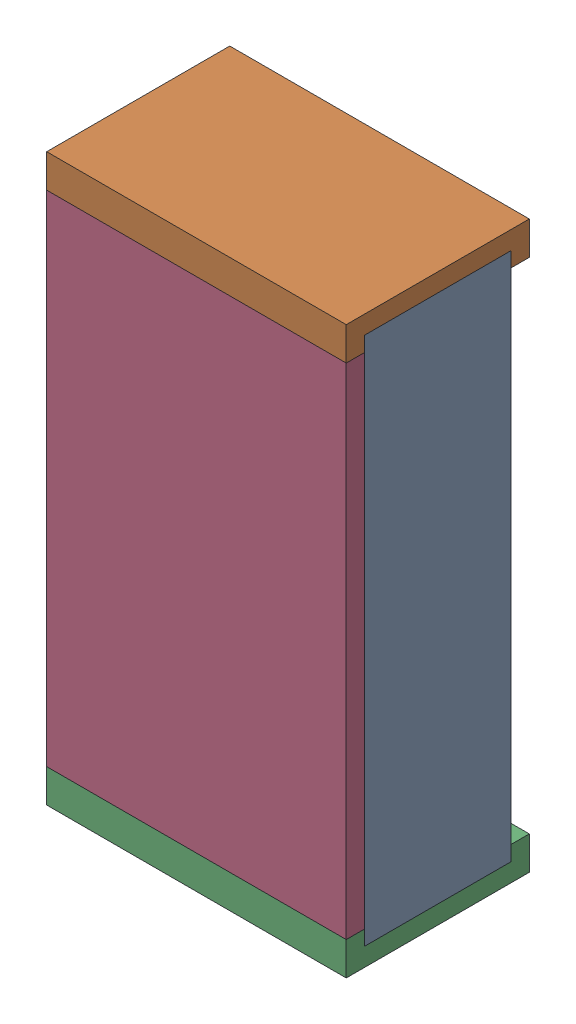
SolidWorks assembly R5, configuration Default. Lengths in mm.
Overall size (0.9 1.7 0.55).
7 component instances, 3 part files, 0 mates.
Components (placement in the parent):
- 6019289920-1: 6019289920 [Default] at (19.3041 -0.0001 0) x (0 -1 0) z (0 0 1) size (1.7 0.9 0.55)
  - Mid_Body_2-1: Mid_Body_2 [Default] at (-0.85 -0.45 0) size (1.59 0.9 0.44)
  - Terminal_2-1: Terminal_2 [Default] at (-0.85 -0.45 0) size (0.1 0.9 0.55)
    - Open CASCADE STEP translator 6.8 15.2.1_2-1: Open CASCADE STEP translator 6.8 15.2.1_2 [Default] at origin size (0.1 0.9 0.55)
  - Terminal_2-2: Terminal_2 [Default] at (0.85 0.45 0) x (-1 0 0) z (0 0 1) size (0.1 0.9 0.55)
    - Open CASCADE STEP translator 6.8 15.2.1_2-1: Open CASCADE STEP translator 6.8 15.2.1_2 [Default] at origin size (0.1 0.9 0.55)
  - Mark_2-1: Mark_2 [Default] at (-0.75 -0.45 0.495) size (1.5 0.9 0.06)
